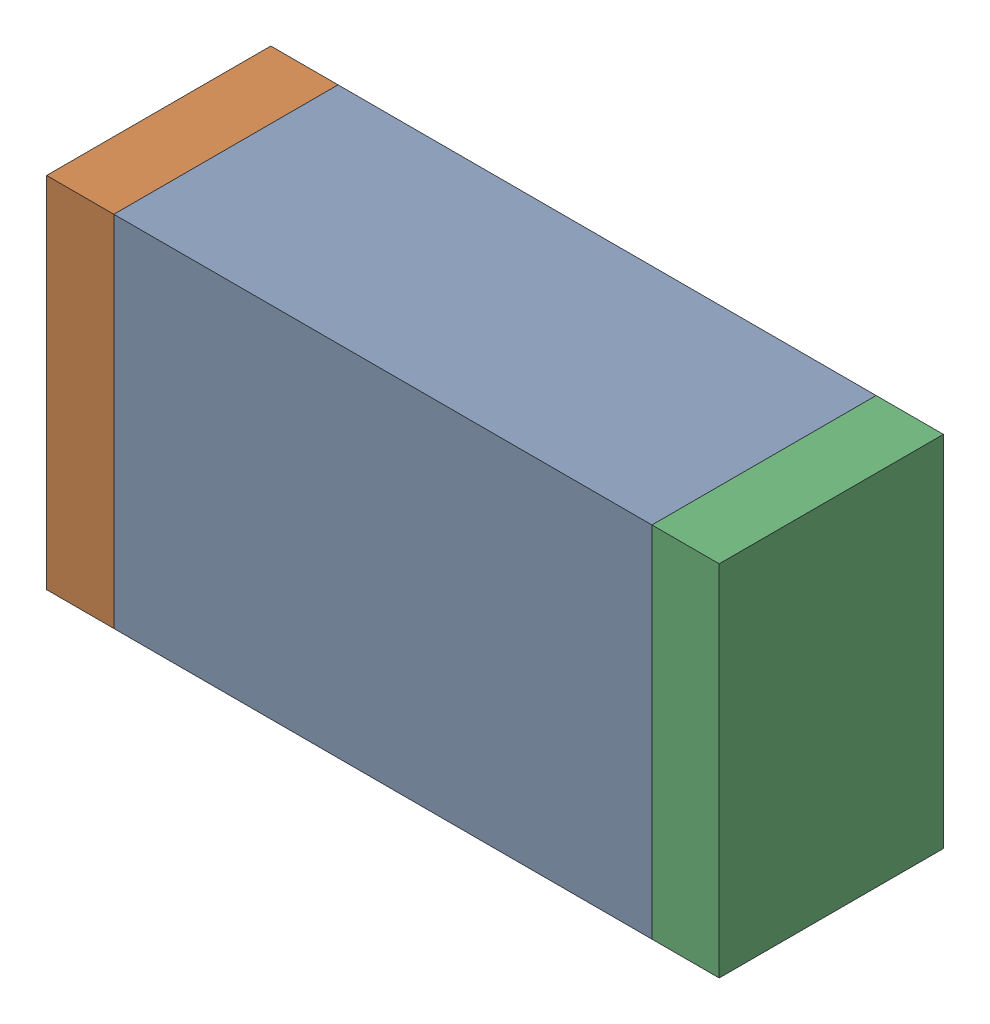
SolidWorks assembly R70, configuration Default. Lengths in mm.
Overall size (1.5 0.8 0.5).
6 component instances, 2 part files, 0 mates.
Components (placement in the parent):
- 836752368-1: 836752368 [Default] at (111.9 76.5 0) size (1.2 0.8 0.5)
  - Extruded-1: Extruded [Default] at origin size (1.2 0.8 0.5)
- 836752496-1: 836752496 [Default] at (111.225 76.5 0) size (0.15 0.8 0.5)
  - Extruded_2-1: Extruded_2 [Default] at origin size (0.15 0.8 0.5)
- 836752496-2: 836752496 [Default] at (112.575 76.5 0) size (0.15 0.8 0.5)
  - Extruded_2-1: Extruded_2 [Default] at origin size (0.15 0.8 0.5)
